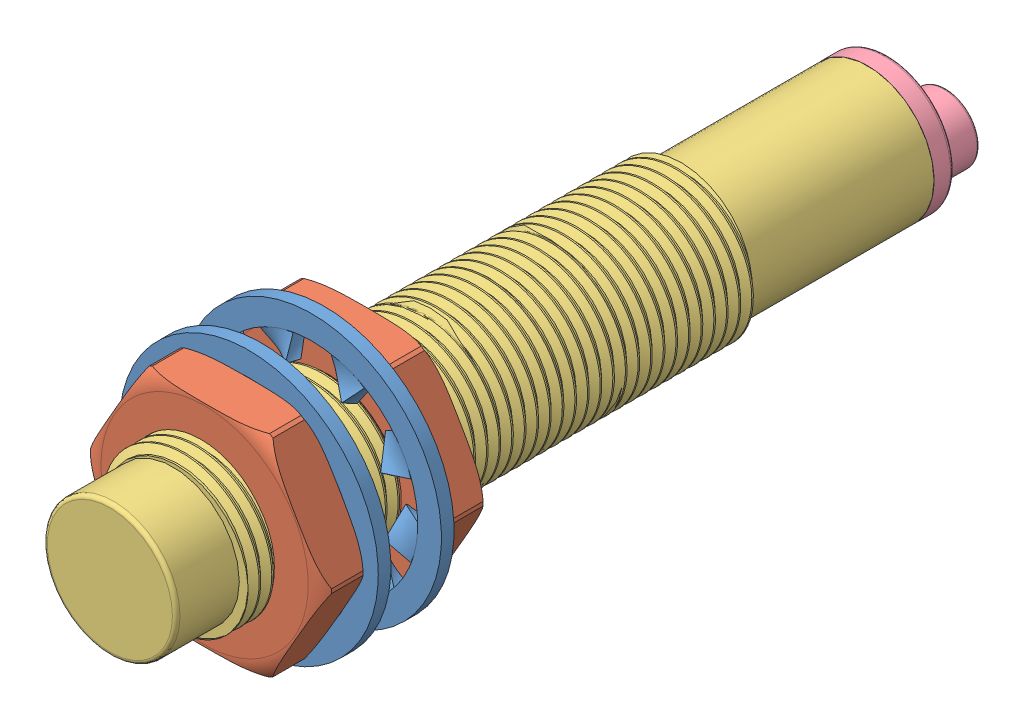
SolidWorks assembly Indutivo, configuration Valor predeterminado. Lengths in mm.
Overall size (20.5 20.5 66.2).
9 component instances, 6 part files, 0 mates.
Components (placement in the parent):
- Indutivo.step-1: Indutivo.step [Valor predeterminado] at origin size (20.5 32.31 86.91)
  - 93925A300.step-1: 93925A300.step [Valor predeterminado] at (-0.0005 -0.0003 -11.5) x (1 0 0) z (0 0 -1) size (20.5 20.5 2.11)
  - 93925A300.step-2: 93925A300.step [Valor predeterminado] at (-0.0006 -0.0007 -16.5) x (1 0 0) z (0 0 -1) size (20.5 20.5 2.11)
  - Nut.step-1: Nut.step [Valor predeterminado] at (-0.0001 -0.0008 -11) size (19.14 16.74 3.53)
  - Nut.step-2: Nut.step [Valor predeterminado] at (-0.0004 -0.0002 -17) x (1 0 0) z (0 0 -1) size (19.14 16.74 3.53)
  - LJ12A3-4-Z_BX.step-1: LJ12A3-4-Z_BX.step [Valor predeterminado] at origin size (11.99 11.98 60)
  - LJ12A3-4-Z_BX-0.step-1: LJ12A3-4-Z_BX-0.step [Valor predeterminado] at origin size (10.5 10.5 6.2)
  - LJ12A3-4-Z_BX-1.step-1: LJ12A3-4-Z_BX-1.step [Valor predeterminado] at origin size (3.5 3.5 1.5)
  - LJ12A3-4-Z_BX-2.step-1: LJ12A3-4-Z_BX-2.step [Valor predeterminado] at origin size (3.54 25.97 25.31) (hidden)
